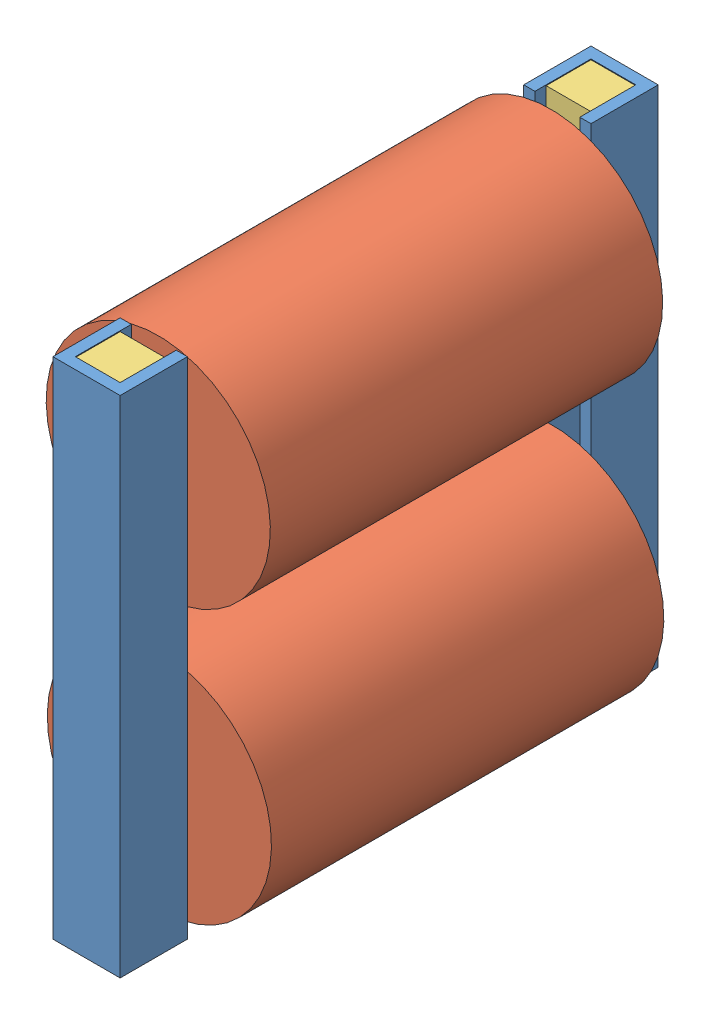
SolidWorks assembly Sheet_metal_roller_simple, configuration Default. Lengths in mm.
Overall size (276.55 518.34 480).
5 component instances, 3 part files, 4 mates.
Components (placement in the parent):
- Rail-1: Rail [Default] at (128.7267 284.0067 582.2893) size (60 450 480)
- Roller-1: Roller [Default] at (128.7267 164.0067 372.2893) x (0.48017 -0.877175 0) z (0 0 1) size (200 200 350)
- Upper_roller-1: Upper_roller [Default] at (502.6888 145.3139 256.8438) x (0 0 1) z (-1 0 0) size (460 276.55 276.55) (flexible)
  - rail_mpver-1: rail_mpver [Default] at (-94.5545 253.0282 373.9621) size (460 220 40)
  - Roller-1: Roller [Default] at (116.4455 263.0282 373.9621) x (0 0.543039 0.839707) z (-1 0 0) size (200 200 350)
Mates (geometry in assembly coordinates):
- Concentric1: concentric anti-aligned: cylinder of Rail-1 through (128.7267 164.0067 372.2893) axis (0 0 1) radius 17.5; cylinder of Roller-1 through (128.7267 164.0067 547.2893) axis (0 0 -1) radius 17.5
- Distance1: distance = 5 mm anti-aligned: plane of Roller-1 through (128.7267 164.0067 547.2893) normal (0 0 1); plane of Rail-1 through (148.7267 509.0067 552.2893) normal (0 0 -1)
- Coincident2: coincident anti-aligned: plane of Rail-1 through (108.7267 509.0067 602.2893) normal (0 0 -1); plane of Upper_roller-1/rail_mpver-1 through (108.7267 508.3421 602.2893) normal (0 0 1)
- Coincident3: coincident anti-aligned: plane of Rail-1 through (148.7267 509.0067 602.2893) normal (-1 0 0); plane of Upper_roller-1/rail_mpver-1 through (148.7267 508.3421 602.2893) normal (1 0 0)
